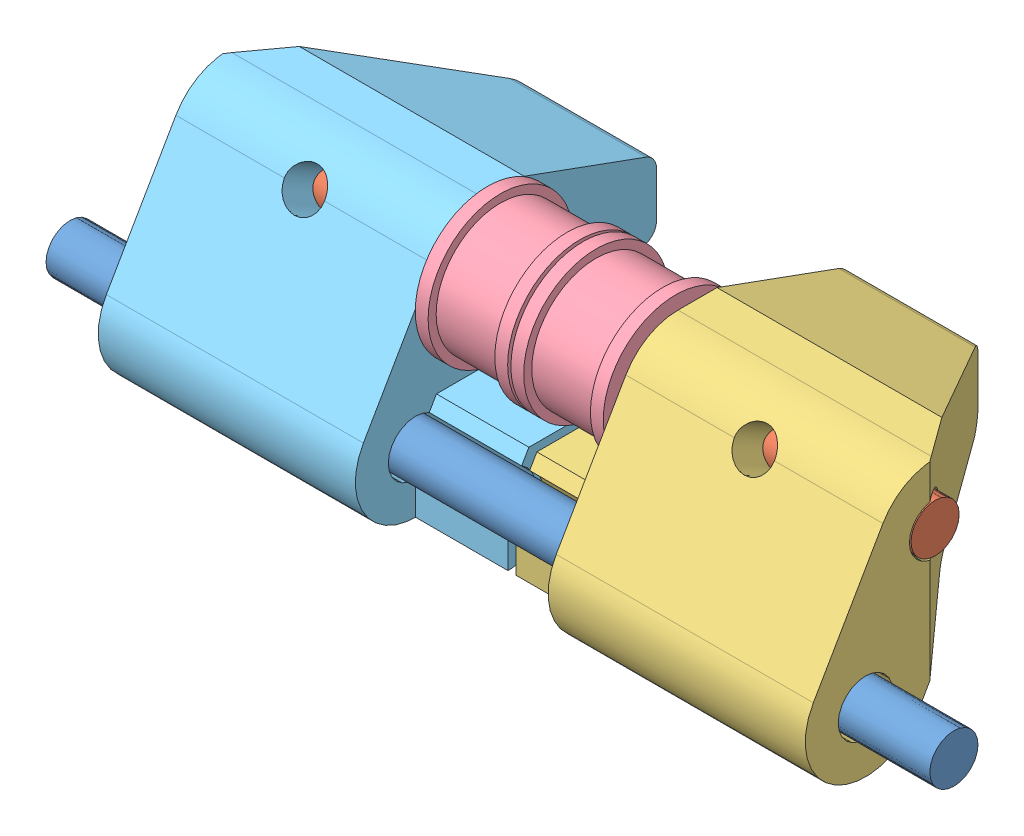
SolidWorks assembly Bobbin_independent_assem_v2, configuration Default. Lengths in mm.
Overall size (55 38.51 37.17).
8 component instances, 6 part files, 17 mates.
Components (placement in the parent):
- shaft_3x55mm-1: shaft_3x55mm [Default] at origin size (55 3 3)
- shaft_3x22mm-1: shaft_3x22mm [Default] at (-22 7.5 -4.3301) x (1 0 0) z (0 0.999928 0.012015) size (22 3 3)
- shaft_3x22mm-2: shaft_3x22mm [Default] at (0 7.5 -4.3301) size (22 3 3)
- idler_differential_arm_v1-1: idler_differential_arm_v1 [Default] at (-3.5647 27.2566 19.248) (suppressed, hidden)
- arm_idler_single_v4-1: arm_idler_single_v4 [Default] at origin size (21.75 15 18.75)
- idler_single_v2-1: idler_single_v2 [Default] at (-2.975 7.5 -4.3301) size (5.75 9 9)
- idler_single_v2-2: idler_single_v2 [Default] at (2.975 7.5 -4.3301) size (5.75 9 9)
- arm_idler_single_v3_mirrored-1: arm_idler_single_v3_mirrored [Default] at (-12 0 0) size (21.75 15 18.75)
Mates (geometry in assembly coordinates):
- Concentric1: concentric aligned: cylinder of shaft_3x55mm-1 through (27.5 0 0) axis (-1 0 0) radius 1.5; cylinder of arm_idler_single_v4-1 through (22 0 0) axis (-1 0 0) radius 1.7
- Concentric2: concentric aligned: cylinder of shaft_3x22mm-2 through (22 8.2083 -2.7611) axis (-1 0 0) radius 1.5; cylinder of arm_idler_single_v4-1 through (22 8.2083 -2.7611) axis (-1 0 0) radius 1.6
- Coincident1: coincident aligned: plane of shaft_3x22mm-2 through (22 8.2083 -2.7611) normal (1 0 0); plane of arm_idler_single_v4-1 through (22 0 0) normal (1 0 0)
- Coincident3: coincident aligned: plane of shaft_3x55mm-1 through (0 0 0) normal (1 0 0); plane of assembly through (0 0 0) normal (1 0 0)
- Coincident4: coincident aligned: plane of shaft_3x55mm-1 through (0 0 0) normal (0 1 0); plane of assembly through (0 0 0) normal (0 1 0)
- Coincident5: coincident aligned: plane of shaft_3x55mm-1 through (0 0 0) normal (0 0 1); plane of assembly through (0 0 0) normal (0 0 1)
- Distance3: distance = 22 mm aligned: plane of arm_idler_single_v4-1 through (22 0 0) normal (1 0 0); plane of assembly through (0 0 0) normal (1 0 0)
- Concentric4: concentric aligned: cylinder of shaft_3x22mm-2 through (22 8.2083 -2.7611) axis (-1 0 0) radius 1.5; cylinder of idler_single_v2-2 through (5.85 8.2083 -2.7611) axis (-1 0 0) radius 3.075
- Concentric5: concentric aligned: cylinder of shaft_3x22mm-1 through (0 7.5 -4.3301) axis (-1 0 0) radius 1.5; cylinder of idler_single_v2-1 through (-0.1 7.5 -4.3301) axis (-1 0 0) radius 3.075
- Concentric6: concentric anti-aligned: cylinder of shaft_3x22mm-1 through (0 7.5 -4.3301) axis (-1 0 0) radius 1.5; cylinder of arm_idler_single_v3_mirrored-1 through (-22 7.5 -4.3301) axis (1 0 0) radius 1.6
- Concentric7: concentric anti-aligned: cylinder of shaft_3x55mm-1 through (27.5 0 0) axis (-1 0 0) radius 1.5; cylinder of arm_idler_single_v3_mirrored-1 through (-22 0 0) axis (1 0 0) radius 1.7
- Coincident8: coincident aligned: plane of shaft_3x22mm-1 through (-22 7.5 -4.3301) normal (-1 0 0); plane of arm_idler_single_v3_mirrored-1 through (-22 0 0) normal (-1 0 0)
- Coincident9: coincident anti-aligned: plane of idler_single_v2-1 through (-5.85 9 -4.3301) normal (-1 0 0); plane of arm_idler_single_v3_mirrored-1 through (-5.85 7.5 -4.3301) normal (1 0 0)
- Coincident10: coincident anti-aligned: plane of arm_idler_single_v4-1 through (5.85 8.2083 -2.7611) normal (-1 0 0); plane of idler_single_v2-2 through (5.85 12.7083 -2.7611) normal (1 0 0)
- Distance4: distance = 22 mm anti-aligned: plane of arm_idler_single_v3_mirrored-1 through (-22 0 0) normal (-1 0 0); plane of assembly through (0 0 0) normal (1 0 0)
- Parallel1: parallel aligned: plane of shaft_3x55mm-1 through (0 0 0) normal (0 1 0); plane of arm_idler_single_v3_mirrored-1 through (-22 11.25 -4.3301) normal (0 1 0)
- Coincident12: coincident aligned: plane of arm_idler_single_v4-1 through (22 11.25 -4.3301) normal (0 1 0); plane of arm_idler_single_v3_mirrored-1 through (-22 11.25 -4.3301) normal (0 1 0)
